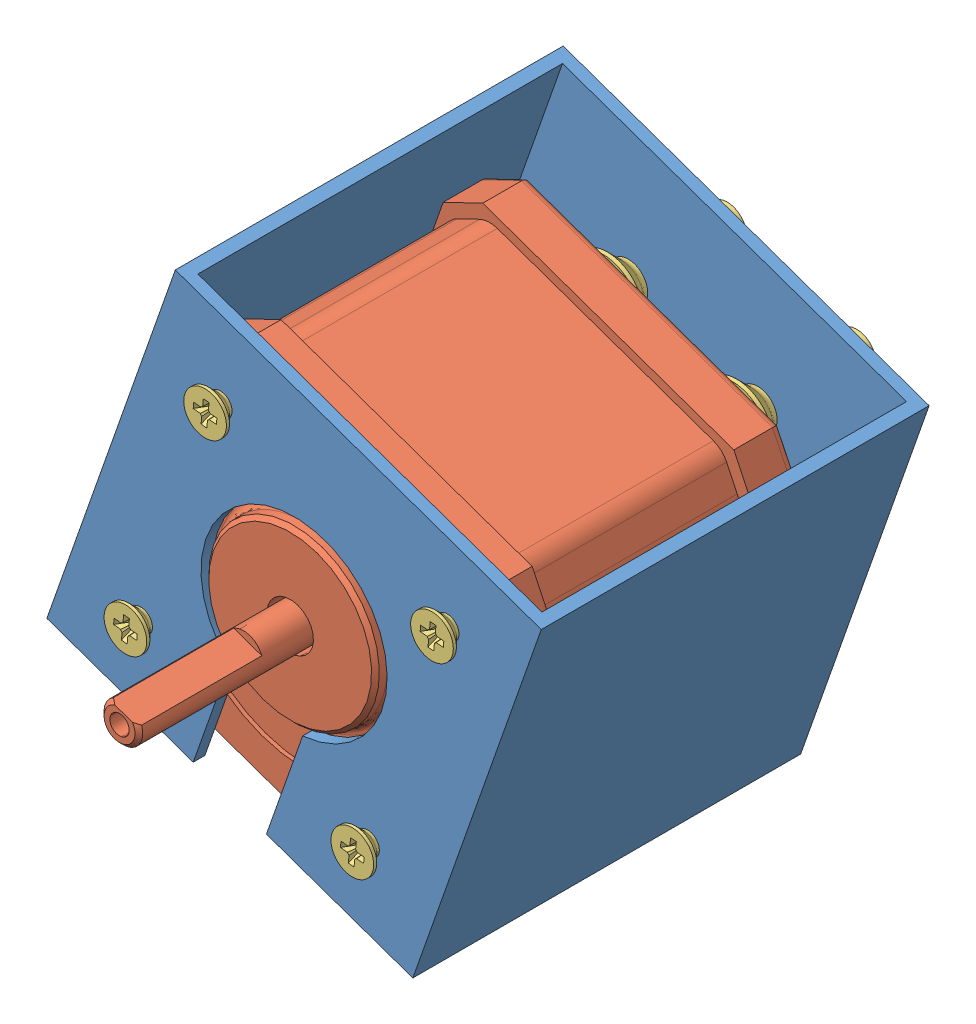
SolidWorks assembly Junta5-Assembly, configuration Valor predeterminado. Lengths in mm.
Overall size (63.74 63.74 83.76).
10 component instances, 3 part files, 10 mates.
Components (placement in the parent):
- Junta 5-1: Junta 5 [Valor predeterminado] at (-13.9464 31.9653 28.2615) x (-0.943555 0.331217 0) z (-0.331217 -0.943555 0) size (50 50 50)
- NEMA17-1: NEMA17 [Défaut] at (-22.2268 8.3764 53.7615) x (0.331217 0.943555 0) z (0 0 -1) size (45.3 42.3 62)
- countersunk flat head cross recess screw_iso-1: countersunk flat head cross recess screw_iso [ISO 7046-1 - M5 x 16 - Z - 16N] at (-10.9593 13.7888 8) x (0 0 -1) z (-0.59254 0.805541 0) size (16 9.3 9.3)
- countersunk flat head cross recess screw_iso-2: countersunk flat head cross recess screw_iso [ISO 7046-1 - M5 x 16 - Z - 16N] at (-16.8145 -2.8911 8) x (0 0 -1) z (-0.59254 0.805541 0) size (16 9.3 9.3)
- countersunk flat head cross recess screw_iso-3: countersunk flat head cross recess screw_iso [ISO 7046-1 - M5 x 16 - Z - 16N] at (-33.4943 2.9641 8) x (0 0 -1) z (-0.59254 0.805541 0) size (16 9.3 9.3)
- countersunk flat head cross recess screw_iso-4: countersunk flat head cross recess screw_iso [ISO 7046-1 - M5 x 16 - Z - 16N] at (-27.6392 19.6439 8) x (0 0 -1) z (-0.59254 0.805541 0) size (16 9.3 9.3)
- countersunk flat head cross recess screw_iso-5: countersunk flat head cross recess screw_iso [ISO 7046-1 - M3 x 6 - Z - 6N] at (-2.4679 17.8677 55.2429) x (0 0 -1) z (0.097442 0.995241 0) size (6 5.5 5.5)
- countersunk flat head cross recess screw_iso-6: countersunk flat head cross recess screw_iso [ISO 7046-1 - M3 x 6 - Z - 6N] at (-41.9858 -1.1148 55.2429) x (0 0 -1) z (0.097442 0.995241 0) size (6 5.5 5.5)
- countersunk flat head cross recess screw_iso-7: countersunk flat head cross recess screw_iso [ISO 7046-1 - M3 x 6 - Z - 6N] at (-31.7181 28.1354 55.2429) x (0 0 -1) z (0.097442 0.995241 0) size (6 5.5 5.5)
- countersunk flat head cross recess screw_iso-8: countersunk flat head cross recess screw_iso [ISO 7046-1 - M3 x 6 - Z - 6N] at (-12.7356 -11.3825 55.2429) x (0 0 -1) z (0.097442 0.995241 0) size (6 5.5 5.5)
Mates (geometry in assembly coordinates):
- Coincident1: coincident: circle of countersunk flat head cross recess screw_iso-3; circle of Junta 5-1
- Coincident2: coincident: circle of countersunk flat head cross recess screw_iso-2; circle of Junta 5-1
- Coincident3: coincident: circle of countersunk flat head cross recess screw_iso-1; circle of Junta 5-1
- Coincident4: coincident: circle of countersunk flat head cross recess screw_iso-4; circle of Junta 5-1
- Coincident6: coincident: circle of Junta 5-1; circle of NEMA17-1
- Coincident7: coincident: circle of Junta 5-1; circle of NEMA17-1
- Coincident8: coincident: circle of countersunk flat head cross recess screw_iso-8; circle of Junta 5-1
- Coincident9: coincident: circle of countersunk flat head cross recess screw_iso-7; circle of Junta 5-1
- Coincident10: coincident: circle of countersunk flat head cross recess screw_iso-5; circle of Junta 5-1
- Coincident11: coincident: circle of countersunk flat head cross recess screw_iso-6; circle of Junta 5-1
